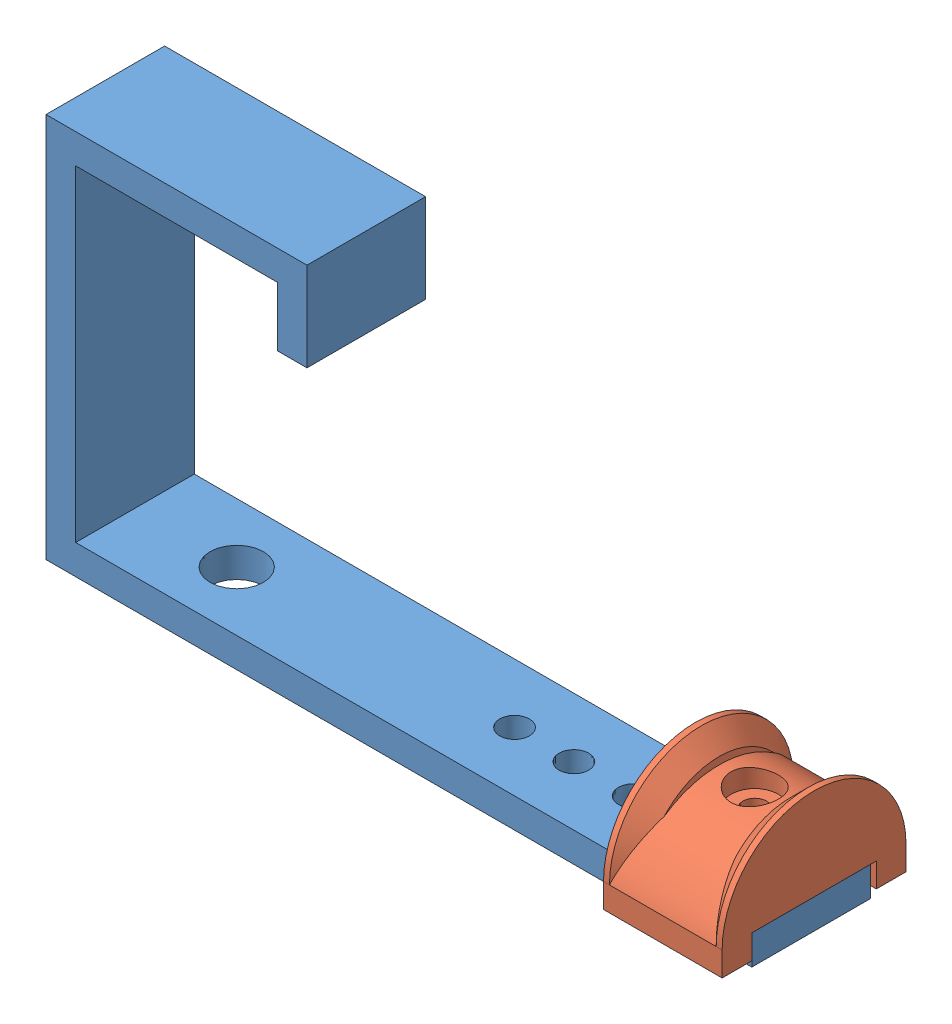
SolidWorks assembly Assemblage1, configuration Défaut. Lengths in mm.
Overall size (119 65 31).
2 component instances, 2 part files, 3 mates.
Components (placement in the parent):
- Pièce1-1: Pièce1 [Défaut] at (-40.9189 7.1155 109) size (119 65 20)
- Pièce2-1: Pièce2 [Défaut] at (51.7067 -27.7319 117.409) x (0 0 1) z (-1 0 0) size (31 19.59 20)
Mates (geometry in assembly coordinates):
- Coïncidente2: coincident: plane of Pièce1-1 through (-40.9189 7.1155 129) normal (0 0 1); plane of Pièce2-1 through (51.4147 -27.7319 129) normal (0 0 -1)
- Coïncidente3: coincident: plane of Pièce1-1 through (-40.9189 -27.7319 129) normal (0 1 0); plane of Pièce2-1 through (31.7067 -27.7319 117.409) normal (0 -1 0)
- Coïncidente4: coincident aligned: plane of Pièce1-1 through (51.7067 7.1155 109) normal (1 0 0); plane of Pièce2-1 through (51.7067 -27.7319 117.409) normal (1 0 0)
